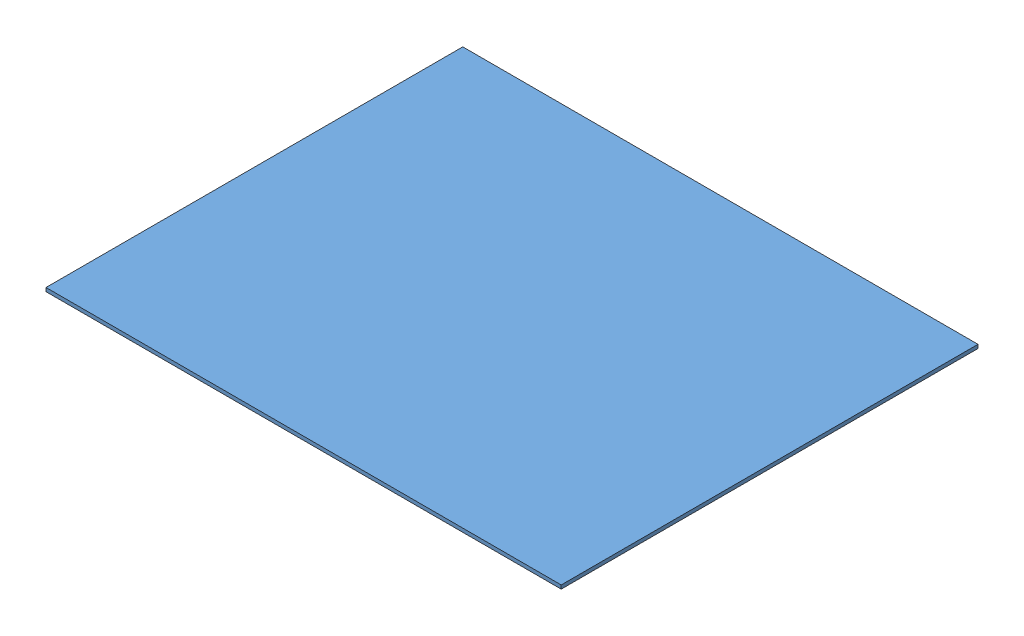
SolidWorks assembly 1.75mm-milling-assembly, configuration Default. Lengths in mm.
Overall size (246 1.75 199).
2 component instances, 2 part files, 3 mates.
Components (placement in the parent):
- stock-1.75mm-1: stock-1.75mm [Default] at origin size (246 1.75 199)
- frame-top-1: frame-top [Default] at (82.5302 0 59.0302) size (78.94 1.75 78.94)
Mates (geometry in assembly coordinates):
- Tangent1: tangent aligned: cylinder of frame-top-1 through (114.35 1.75 90.85) axis (0 -1 0) radius 7.65; plane of assembly
- Tangent2: tangent aligned: cylinder of frame-top-1 through (114.35 1.75 90.85) axis (0 -1 0) radius 7.65; plane of assembly
- Coincident1: coincident aligned: plane of stock-1.75mm-1 through (0 0 0) normal (0 -1 0); plane of frame-top-1 through (82.5302 0 59.0302) normal (0 -1 0)
